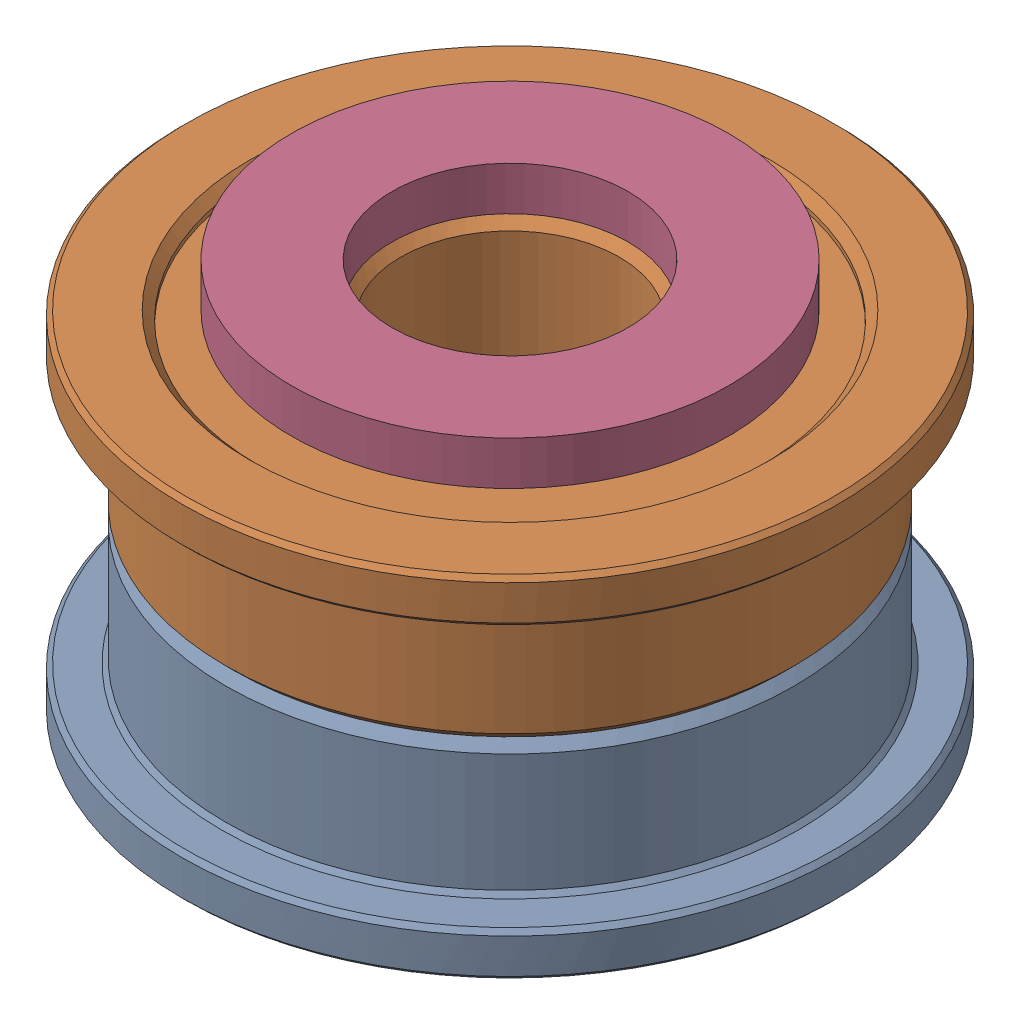
SolidWorks assembly Idler Pulley Assembly v3_2, configuration Default. Lengths in mm.
Overall size (15 10 15).
4 component instances, 3 part files, 0 mates.
Components (placement in the parent):
- F695-2RS v1 (1)-1: F695-2RS v1 (1) [Default] at origin size (15 4 15)
- F695-2RS v1 (2)-1: F695-2RS v1 (2) [Default] at (0 8 0) x (-1 0 0) z (0 0 1) size (15 4 15)
- M5 1mm Spacer-1: M5 1mm Spacer [Default] at (0 0 -350) size (10 1 10)
- M5 1mm Spacer-2: M5 1mm Spacer [Default] at (0 9 -350) size (10 1 10)
